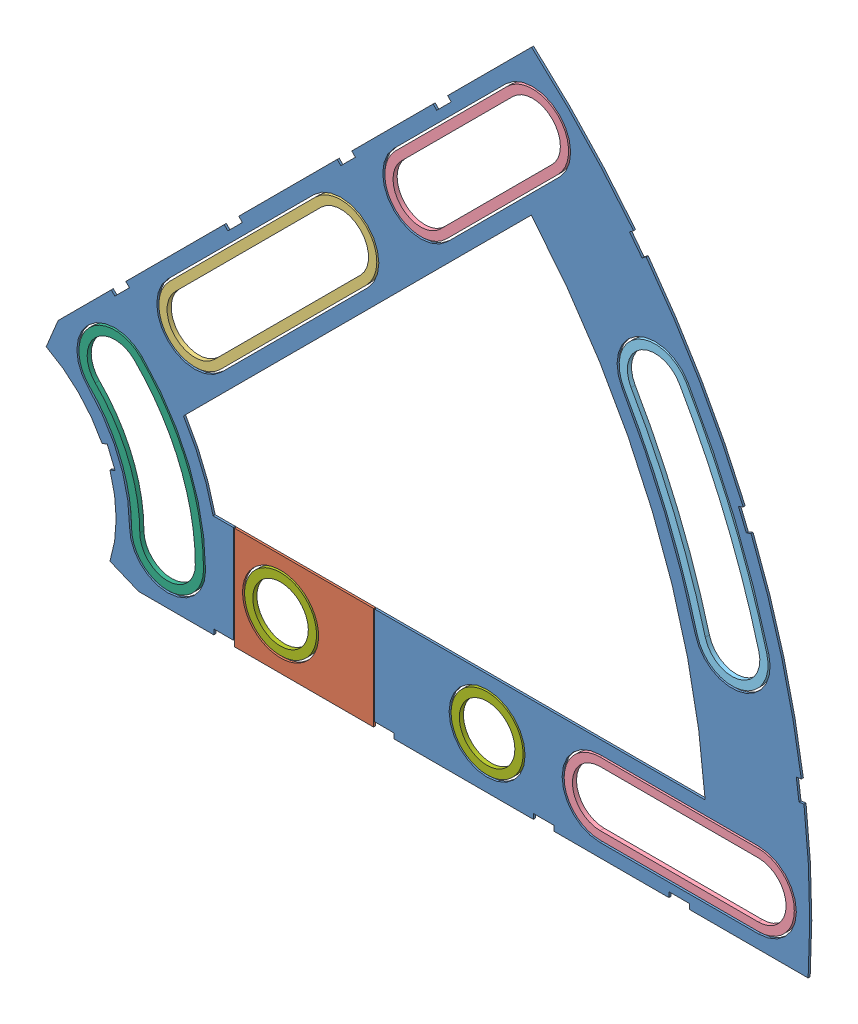
SolidWorks assembly Clover_11_Insul+Pass, configuration Default. Lengths in mm.
Overall size (96.77 82.54 0.51).
9 component instances, 7 part files, 22 mates.
Components (placement in the parent):
- Clover_11_Insul-1: Clover_11_Insul [Default] at (-21.2674 15.3623 72.7047) size (94.37 82.54 0.25)
- Clover_11_Pass-1: Clover_11_Pass [Default] at (-21.2674 15.3623 72.7047) size (17.21 12.7 0.25)
- Clover_Long_Washer-1: Clover_Long_Washer [Default] at (13.3514 49.9812 72.9587) x (0.707107 0.707107 0) z (-0.707107 0.707107 0) size (34.42 0.51 8.89)
- Clover_Med_Washer-1: Clover_Med_Washer [Default] at (39.1697 75.7994 72.9587) x (0.707107 0.707107 0) z (-0.707107 0.707107 0) size (28.45 0.51 8.89)
- Clover_Med_Washer-2: Clover_Med_Washer [Default] at (64.2036 15.3623 72.9587) x (1 0 0) z (0 1 0) size (28.45 0.51 8.89)
- Clover_Outside_Washer-1: Clover_Outside_Washer [Default] at (-21.2674 15.3623 72.9587) x (0.866025 0.5 0) z (-0.5 0.866025 0) size (12.14 0.51 33.54)
- Curve_Inner_Washer-1: Curve_Inner_Washer [Default] at (-21.2674 15.3623 72.9587) x (0.707107 0.707107 0) z (-0.707107 0.707107 0) size (15.4 0.51 24.61)
- Round_Washer-1: Round_Washer [Default] at (14.9276 15.3623 72.9587) x (1 0 0) z (0 1 0) size (8.89 0.51 8.89)
- Round_Washer-2: Round_Washer [Default] at (40.4546 15.3623 72.9587) x (1 0 0) z (0 1 0) size (8.89 0.51 8.89)
Mates (geometry in assembly coordinates):
- Coincident2: coincident: plane of Clover_11_Insul-1 through (-21.2674 15.3623 72.9587) normal (0 0 1); plane of Clover_11_Pass-1 through (-21.2674 15.3623 72.9587) normal (0 0 1)
- Coincident3: coincident: plane of Clover_11_Insul-1 through (67.4055 21.7123 72.9587) normal (0 1 0); plane of Clover_11_Pass-1 through (67.4055 21.7123 72.9587) normal (0 1 0)
- Distance1: distance = 2.54 mm: plane of Clover_11_Insul-1 through (6.6726 9.0123 72.7047) normal (1 0 0); plane of Clover_11_Pass-1 through (9.2126 9.0123 72.7047) normal (-1 0 0)
- Concentric1: concentric: circle of Clover_11_Pass-1; circle of Round_Washer-1
- Coincident4: coincident: plane of Clover_11_Pass-1 through (-21.2674 15.3623 72.9587) normal (0 0 1); plane of Round_Washer-1 through (14.9276 15.3623 72.9587) normal (0 0 1)
- Concentric2: concentric: circle of Clover_11_Insul-1; circle of Round_Washer-2
- Coincident5: coincident: plane of Clover_11_Insul-1 through (-21.2674 15.3623 72.9587) normal (0 0 1); plane of Round_Washer-2 through (40.4546 15.3623 72.9587) normal (0 0 1)
- Concentric3: concentric: circle of Clover_11_Insul-1; circle of Clover_Med_Washer-2
- Concentric4: concentric: circle of Clover_11_Insul-1; circle of Clover_Med_Washer-2
- Coincident6: coincident: plane of Clover_11_Insul-1 through (-21.2674 15.3623 72.9587) normal (0 0 1); plane of Clover_Med_Washer-2 through (54.4246 15.3623 72.9587) normal (0 0 1)
- Concentric5: concentric: circle of Clover_11_Insul-1; circle of Clover_Outside_Washer-1
- Concentric6: concentric: circle of Clover_11_Insul-1; circle of Clover_Outside_Washer-1
- Coincident7: coincident: plane of Clover_11_Insul-1 through (-21.2674 15.3623 72.9587) normal (0 0 1); plane of Clover_Outside_Washer-1 through (19.977 39.1748 72.9587) normal (0 0 1)
- Concentric7: concentric: circle of Clover_11_Insul-1; circle of Clover_Med_Washer-1
- Concentric8: concentric: circle of Clover_11_Insul-1; circle of Clover_Med_Washer-1
- Coincident8: coincident: plane of Clover_11_Insul-1 through (-21.2674 15.3623 72.9587) normal (0 0 1); plane of Clover_Med_Washer-1 through (32.2549 68.8846 72.9587) normal (0 0 1)
- Concentric9: concentric: circle of Clover_11_Insul-1; circle of Clover_Long_Washer-1
- Concentric10: concentric: circle of Clover_11_Insul-1; circle of Clover_Long_Washer-1
- Coincident9: coincident: plane of Clover_11_Insul-1 through (-21.2674 15.3623 72.9587) normal (0 0 1); plane of Clover_Long_Washer-1 through (4.3263 40.956 72.9587) normal (0 0 1)
- Concentric11: concentric: circle of Clover_11_Insul-1; circle of Curve_Inner_Washer-1
- Concentric12: concentric: circle of Clover_11_Insul-1; circle of Curve_Inner_Washer-1
- Coincident10: coincident: plane of Clover_11_Insul-1 through (-21.2674 15.3623 72.9587) normal (0 0 1); plane of Curve_Inner_Washer-1 through (-13.4097 23.22 72.9587) normal (0 0 1)
